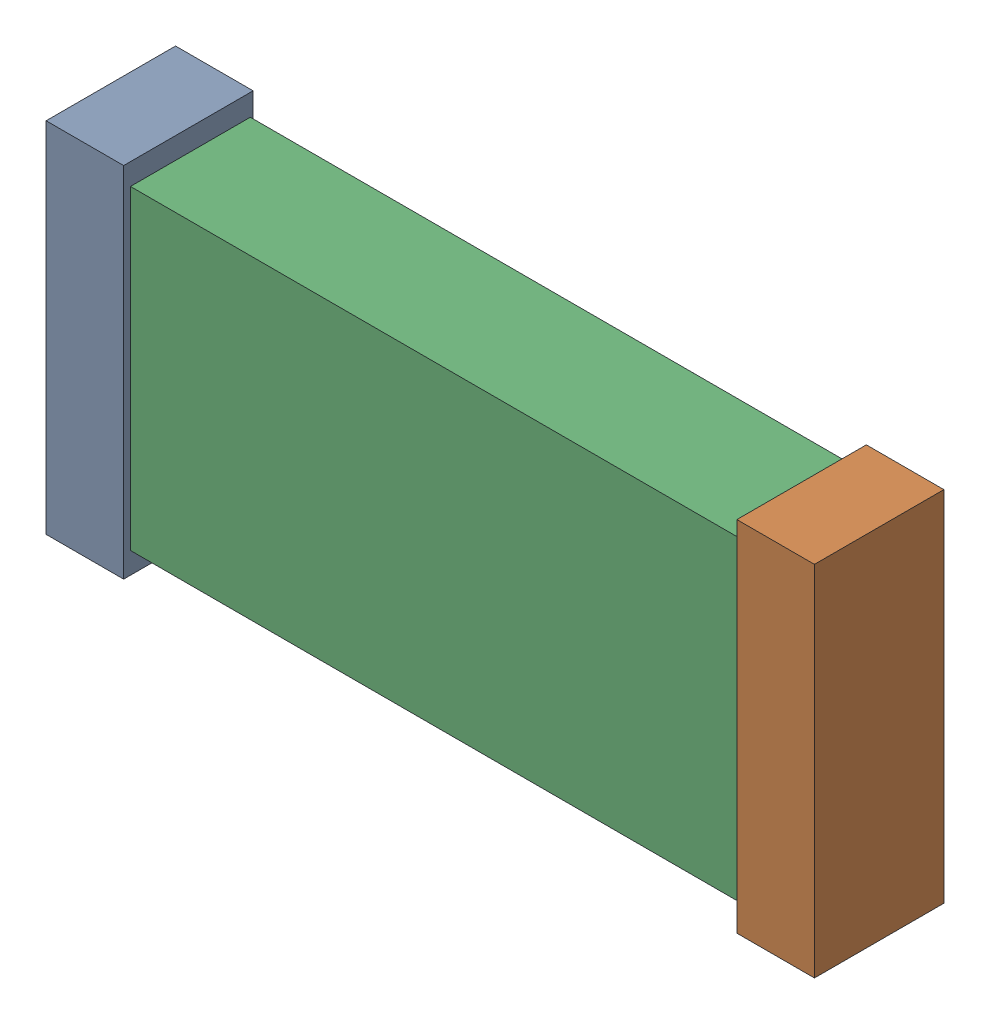
SolidWorks assembly C12, configuration Default. Lengths in mm.
Overall size (2.72 1.27 0.46).
6 component instances, 2 part files, 0 mates.
Components (placement in the parent):
- 432117136_2-1: 432117136_2 [Default] at (42.9816 14.0225 -0.8715) size (0.28 1.27 0.46)
  - Extruded (25)-1: Extruded (25) [Default] at origin size (0.28 1.27 0.46)
- 432117136_3-1: 432117136_3 [Default] at (45.4305 14.0225 -0.8715) size (0.28 1.27 0.46)
  - Extruded (25)-1: Extruded (25) [Default] at origin size (0.28 1.27 0.46)
- 432120848_1-1: 432120848_1 [Default] at (44.15 14.0225 -0.8615) size (2.29 1.12 0.42)
  - Extruded (26)-1: Extruded (26) [Default] at origin size (2.29 1.12 0.42)
